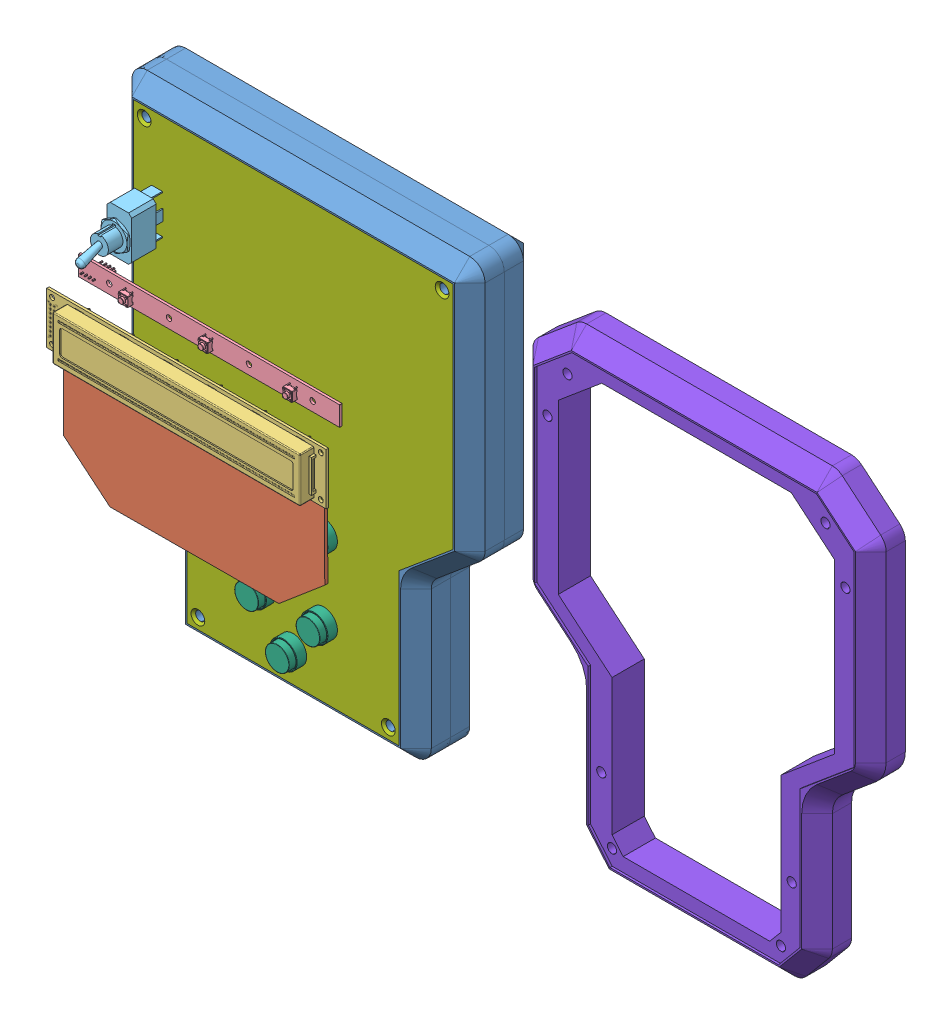
SolidWorks assembly Montagem1, configuration Valor predeterminado. Lengths in mm.
Overall size (491.15 300 123.2).
17 component instances, 9 part files, 23 mates.
Components (placement in the parent):
- 2 - TEC02 - Moldura-1: 2 - TEC02 - Moldura [Valor predeterminado] at (10.4852 -183.9944 348.75) size (230 300 22.5)
- Placa-1: Placa [Valor predeterminado] at (10.9721 -67.3658 434.0244) x (0.999991 0.004139 0) z (0 0 1) size (170 70 2)
- LCD Display 4002-1: LCD Display 4002 [Valor predeterminado] at (10.1028 22.6912 435.8065) size (182 33.5 13.65)
- Teclado_Superior-1: Teclado_Superior [Valor predeterminado] at (-72.6851 -17.0654 427.8625) size (170.25 12.75 19.2)
- BCV3 112 103 - Controle chave geral-1: BCV3 112 103 - Controle chave geral [Default] at (-51.463 76.1571 414.4507) size (17 29 51.5)
- BCV3 112 103 - Controle chave geral-2: BCV3 112 103 - Controle chave geral [Default] at (73.8372 78.9147 386.7098) size (17 29 51.5) (hidden)
- BCV3 112 102 - Controle botão-1: BCV3 112 102 - Controle botão [Valor predeterminado] at (10.4852 -152.9944 371.25) x (0.857411 0.514632 0) z (0.514632 -0.857411 0) size (17.7 39.7 17.7)
- BCV3 112 102 - Controle botão-2: BCV3 112 102 - Controle botão [Valor predeterminado] at (10.4852 -102.9944 371.25) x (1 0 0) z (0 -1 0) size (17.7 39.7 17.7)
- BCV3 112 102 - Controle botão-3: BCV3 112 102 - Controle botão [Valor predeterminado] at (-9.5148 -77.9944 371.25) x (1 0 0) z (0 -1 0) size (17.7 39.7 17.7)
- BCV3 112 102 - Controle botão-4: BCV3 112 102 - Controle botão [Valor predeterminado] at (30.4852 -77.9944 371.25) x (1 0 0) z (0 -1 0) size (17.7 39.7 17.7)
- BCV3 112 102 - Controle botão-5: BCV3 112 102 - Controle botão [Valor predeterminado] at (-9.5148 -127.9944 371.25) x (0.999893 0.014632 0) z (0.014632 -0.999893 0) size (17.7 39.7 17.7)
- BCV3 112 102 - Controle botão-6: BCV3 112 102 - Controle botão [Valor predeterminado] at (30.4852 -127.9944 371.25) x (0.999995 0.003109 0) z (0.003109 -0.999995 0) size (17.7 39.7 17.7)
- BCV3 112 102 - Controle botão-7: BCV3 112 102 - Controle botão [Valor predeterminado] at (6.8304 80.0102 404.5628) x (1 0 0) z (0 -1 0) size (17.7 39.7 17.7) (hidden)
- 2 - TEC02 - Moldura-2: 2 - TEC02 - Moldura [Valor predeterminado] at (10.4852 -183.9944 348.75) x (-1 0 0) z (0 0 -1) size (230 300 22.5)
- 2 - TEC03 - Chapa Inferior-1: 2 - TEC03 - Chapa Inferior [Valor predeterminado] at (7.3461 -35.991 327.75) x (-1 0 0) z (0 0 -1) size (208 278 1.5) (hidden)
- 2 - TEC04 - Chapa Superior-1: 2 - TEC04 - Chapa Superior [Valor predeterminado] at (13.6242 -35.991 369.75) size (208 278 1.5)
- 3 - TEC02 - Moldura-1: 3 - TEC02 - Moldura [Valor predeterminado] at (271.6343 -183.9944 348.75) size (230 300 22.5)
Mates (geometry in assembly coordinates):
- Coincidente7: coincident anti-aligned: plane of 2 - TEC02 - Moldura-1 through (10.4852 -183.9944 348.75) normal (0 0 -1); plane of 2 - TEC02 - Moldura-2 through (10.4852 -183.9944 348.75) normal (0 0 1)
- Coincidente8: coincident aligned: plane of 2 - TEC02 - Moldura-1 through (10.4852 116.0056 371.25) normal (0 1 0); plane of 2 - TEC02 - Moldura-2 through (10.4852 116.0056 326.25) normal (0 1 0)
- Coincidente9: coincident aligned: plane of 2 - TEC02 - Moldura-1 through (-104.5148 -183.9944 371.25) normal (-1 0 0); plane of 2 - TEC02 - Moldura-2 through (-104.5148 -183.9944 326.25) normal (-1 0 0)
- Coincidente10: coincident anti-aligned: plane of 2 - TEC02 - Moldura-2 through (10.4852 -183.9944 327.75) normal (0 0 -1); plane of 2 - TEC03 - Chapa Inferior-1 through (7.3461 -35.991 327.75) normal (0 0 1)
- Coincidente11: coincident anti-aligned: plane of 2 - TEC02 - Moldura-2 through (114.4852 105.0056 327.75) normal (-1 0 0); plane of 2 - TEC03 - Chapa Inferior-1 through (114.4852 105.0056 326.25) normal (1 0 0)
- Coincidente12: coincident anti-aligned: plane of 2 - TEC02 - Moldura-2 through (114.4852 -44.8334 327.75) normal (-0.642788 0.766044 0); plane of 2 - TEC03 - Chapa Inferior-1 through (114.4852 -44.8334 326.25) normal (0.642788 -0.766044 0)
- Concêntrico1: concentric aligned: cylinder of BCV3 112 102 - Controle botão-1 through (10.4852 -152.9944 349.95) axis (0 0 1) radius 7.25; cylinder of 2 - TEC04 - Chapa Superior-1 through (10.4852 -152.9944 369.75) axis (0 0 1) radius 8
- Concêntrico2: concentric aligned: cylinder of BCV3 112 102 - Controle botão-5 through (-9.5148 -127.9944 349.95) axis (0 0 1) radius 7.25; cylinder of 2 - TEC04 - Chapa Superior-1 through (-9.5148 -127.9944 369.75) axis (0 0 1) radius 8
- Concêntrico3: concentric aligned: cylinder of BCV3 112 102 - Controle botão-2 through (10.4852 -102.9944 349.95) axis (0 0 1) radius 7.25; cylinder of 2 - TEC04 - Chapa Superior-1 through (10.4852 -102.9944 369.75) axis (0 0 1) radius 8
- Concêntrico4: concentric aligned: cylinder of BCV3 112 102 - Controle botão-4 through (30.4852 -77.9944 349.95) axis (0 0 1) radius 7.25; cylinder of 2 - TEC04 - Chapa Superior-1 through (30.4852 -77.9944 369.75) axis (0 0 1) radius 8
- Concêntrico5: concentric aligned: cylinder of BCV3 112 102 - Controle botão-3 through (-9.5148 -77.9944 349.95) axis (0 0 1) radius 7.25; circle of 2 - TEC04 - Chapa Superior-1
- Concêntrico6: concentric aligned: cylinder of BCV3 112 102 - Controle botão-6 through (30.4852 -127.9944 349.95) axis (0 0 1) radius 7.25; cylinder of 2 - TEC04 - Chapa Superior-1 through (30.4852 -127.9944 369.75) axis (0 0 1) radius 8
- Coincidente13: coincident anti-aligned: plane of BCV3 112 102 - Controle botão-1 through (10.4852 -152.9944 371.25) normal (0 0 -1); plane of 2 - TEC04 - Chapa Superior-1 through (13.6242 -35.991 371.25) normal (0 0 1)
- Coincidente14: coincident anti-aligned: plane of BCV3 112 102 - Controle botão-3 through (-9.5148 -77.9944 371.25) normal (0 0 -1); plane of 2 - TEC04 - Chapa Superior-1 through (13.6242 -35.991 371.25) normal (0 0 1)
- Coincidente15: coincident anti-aligned: plane of BCV3 112 102 - Controle botão-5 through (-9.5148 -127.9944 371.25) normal (0 0 -1); plane of 2 - TEC04 - Chapa Superior-1 through (13.6242 -35.991 371.25) normal (0 0 1)
- Coincidente16: coincident anti-aligned: plane of BCV3 112 102 - Controle botão-2 through (10.4852 -102.9944 371.25) normal (0 0 -1); plane of 2 - TEC04 - Chapa Superior-1 through (13.6242 -35.991 371.25) normal (0 0 1)
- Coincidente17: coincident anti-aligned: plane of BCV3 112 102 - Controle botão-4 through (30.4852 -77.9944 371.25) normal (0 0 -1); plane of 2 - TEC04 - Chapa Superior-1 through (13.6242 -35.991 371.25) normal (0 0 1)
- Coincidente18: coincident anti-aligned: plane of BCV3 112 102 - Controle botão-6 through (30.4852 -127.9944 371.25) normal (0 0 -1); plane of 2 - TEC04 - Chapa Superior-1 through (13.6242 -35.991 371.25) normal (0 0 1)
- Coincidente19: coincident anti-aligned: plane of 2 - TEC02 - Moldura-1 through (114.4852 105.0056 369.75) normal (-1 0 0); plane of 2 - TEC04 - Chapa Superior-1 through (114.4852 105.0056 371.25) normal (1 0 0)
- Coincidente20: coincident anti-aligned: plane of 2 - TEC02 - Moldura-1 through (10.4852 -183.9944 369.75) normal (0 0 1); plane of 2 - TEC04 - Chapa Superior-1 through (13.6242 -35.991 369.75) normal (0 0 -1)
- Coincidente21: coincident anti-aligned: plane of 2 - TEC02 - Moldura-1 through (114.4852 105.0056 369.75) normal (0 -1 0); plane of 2 - TEC04 - Chapa Superior-1 through (114.4852 105.0056 371.25) normal (0 1 0)
- Coincidente22: coincident: plane of 2 - TEC02 - Moldura-1 through (10.4852 -183.9944 371.25) normal (0 -1 0); plane of 3 - TEC02 - Moldura-1 through (271.6343 -183.9944 371.25) normal (0 -1 0)
- Coincidente23: coincident aligned: plane of 2 - TEC02 - Moldura-1 through (10.4852 -183.9944 371.25) normal (0 0 1); plane of 3 - TEC02 - Moldura-1 through (271.6343 -183.9944 371.25) normal (0 0 1)
